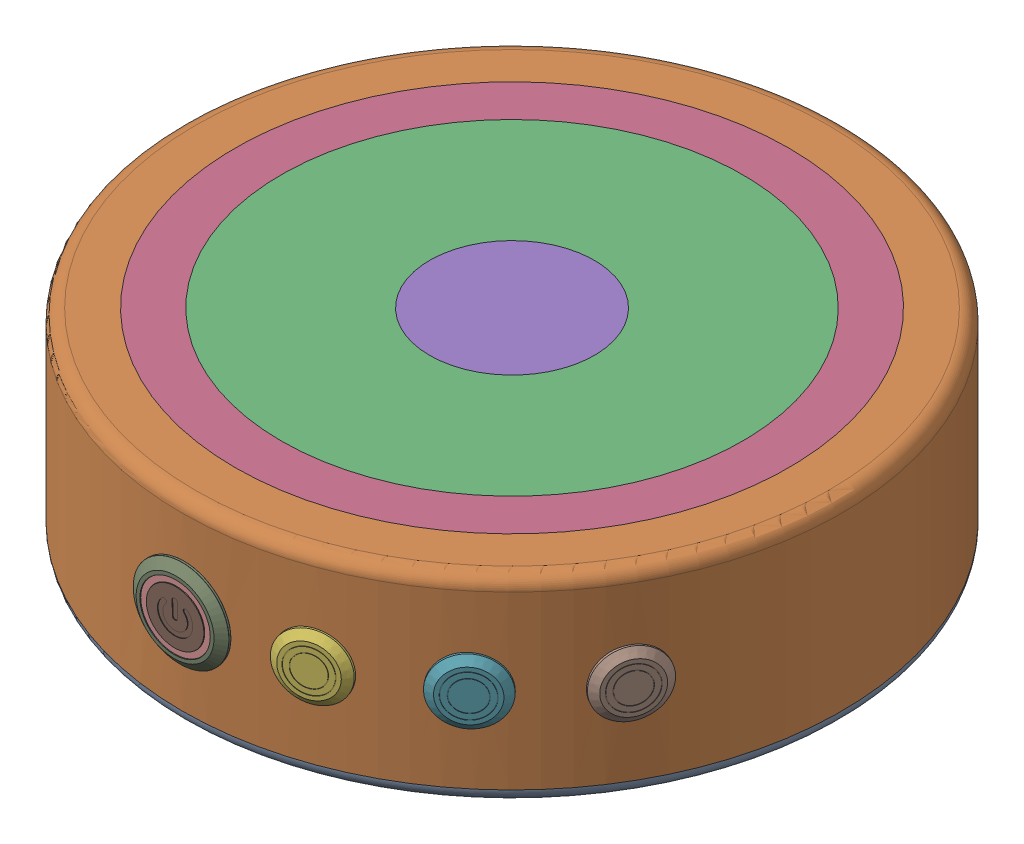
SolidWorks assembly Assem1, configuration Default. Lengths in mm.
Overall size (100 30 101.69).
8 component instances, 6 part files, 6 mates.
Components (placement in the parent):
- Casing bottom-1: Casing bottom [Default] at (-5.9002 -6.25 7.3596) size (100 2 100)
- Outer Casing-1: Outer Casing [Default] at (-5.9002 -4.25 7.3596) size (100 28 100)
- Glass-2: Glass [Default] at (-5.9002 21.75 7.3596) size (84 2 84)
- Push_btn-3: Push_btn [По умолчанию] at (11.9878 8.7495 56.9736) x (-0.359306 0 -0.93322) z (0.93322 0.000282 -0.359305) size (10.85 9.85 9.85)
- Push_btn-6: Push_btn [По умолчанию] at (27.878 8.7495 47.8634) x (-0.656817 0 -0.75405) z (0.75405 0.000282 -0.656817) size (10.85 9.85 9.85)
- Push_btn-7: Push_btn [По умолчанию] at (39.694 8.7495 33.8679) x (-0.875106 0 -0.483931) z (0.483931 0.000282 -0.875106) size (10.85 9.85 9.85)
- Btn19PWR-LED-2: Btn19PWR-LED [По умолчанию] at (-6.169 8.9091 51.4661) x (0.998926 0.000636 -0.046329) z (-0.000636 -0.999624 -0.027424) size (13.91 10.79 13.91)
- COB LED 3W circular-2: COB LED 3W circular [Default] at (-5.9002 18.75 7.3596) x (0 0 -1) z (0 1 0) size (27.83 27.83 2.3)
Mates (geometry in assembly coordinates):
- Coincident1: coincident aligned: circle of Casing bottom-1; circle of Outer Casing-1
- Coincident2: coincident aligned: circle of Outer Casing-1; circle of Glass-2
- Tangent4: tangent: curve of Outer Casing-1; circle of Push_btn-3
- Tangent5: tangent: curve of Outer Casing-1; circle of Btn19PWR-LED-2
- Concentric3: concentric anti-aligned: circle of Outer Casing-1; circle of COB LED 3W circular-2
- Coincident4: coincident anti-aligned: plane of Outer Casing-1 through (-5.9002 19.75 7.3596) normal (0 -1 0); plane of COB LED 3W circular-2 through (-5.9002 19.75 7.3596) normal (0 1 0)
